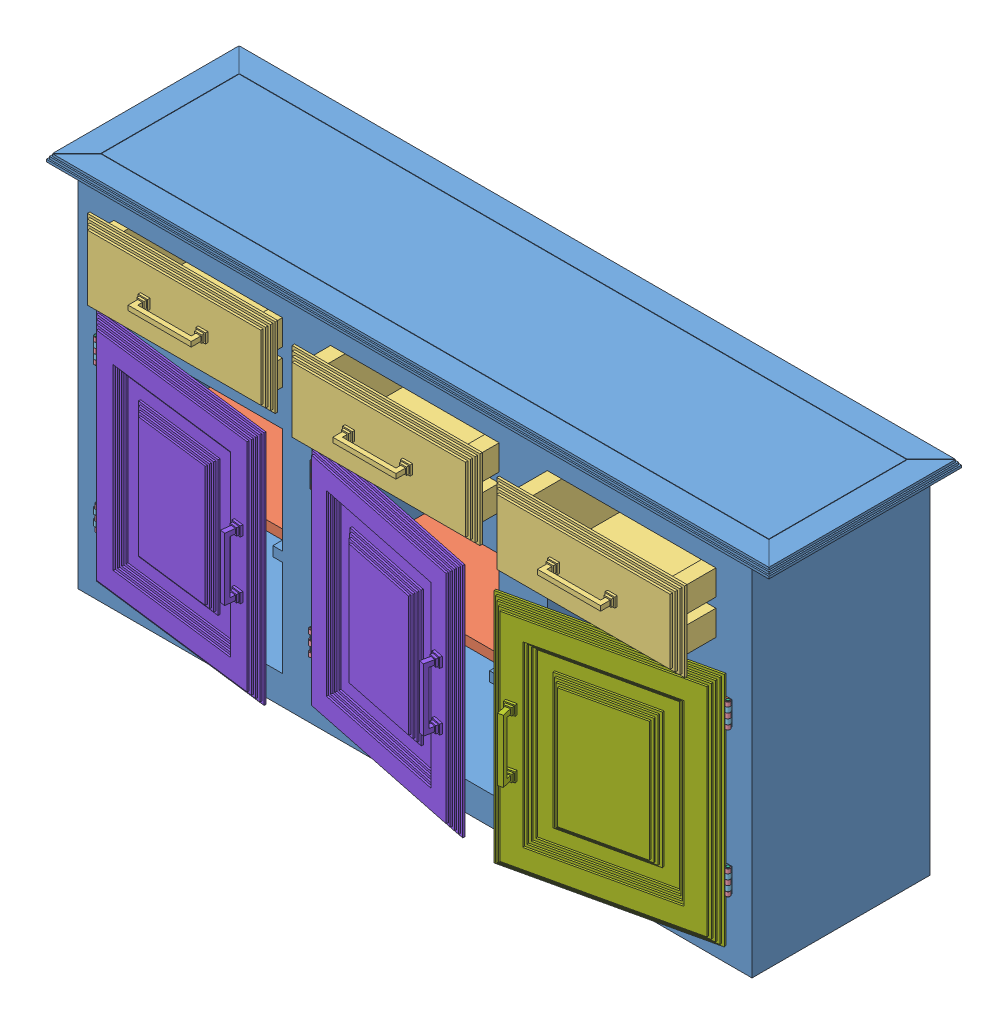
SolidWorks assembly Big.Cupboard, configuration Default. Lengths in mm.
Overall size (1500 765 525.59).
28 component instances, 8 part files, 91 mates.
Components (placement in the parent):
- Big.C-Part 01-1: Big.C-Part 01 [Default] at (578.0567 1072.5023 944.9709) size (1500 765 400)
- Big.C-Part 02-1: Big.C-Part 02 [Default] at (303.0567 602.5023 1109.9709) size (350 20 300)
- Big.C-Part 02-2: Big.C-Part 02 [Default] at (753.0567 602.5023 1109.9709) size (350 20 300)
- Big.C-Part 02-3: Big.C-Part 02 [Default] at (1203.0567 602.5023 1109.9709) size (350 20 300)
- Big.C-Part 03-1: Big.C-Part 03 [Default] at (128.0567 691.1413 859.9709) size (390 165 350)
- Big.C-Part 03-2: Big.C-Part 03 [Default] at (578.0567 691.1413 884.9709) size (390 165 350)
- Big.C-Part 03-3: Big.C-Part 03 [Default] at (1028.0567 691.1413 909.9709) size (390 165 350)
- HINGE HALF A-1: HINGE HALF A [Default] at (-77.5483 777.6273 1135.558) x (0.992303 0 0.123831) z (0 1 0) size (45.16 9.11 50.13)
- HINGE HALF B-1: HINGE HALF B [Default] at (-77.5483 777.5023 1135.558) x (0 0 -1) z (0 1 0) size (45.14 9.11 98.89)
- HINGE PIN-1: HINGE PIN [Default] at (-77.5483 804.6273 1135.558) x (0 -1 0) z (0.656059 0 0.75471) size (53.5 7 7)
- HINGE HALF A-2: HINGE HALF A [Default] at (372.4517 777.6273 1135.558) x (0.979214 0 0.202829) z (0 1 0) size (45.16 9.11 50.13)
- HINGE HALF B-2: HINGE HALF B [Default] at (372.4517 777.5023 1135.558) x (0 0 -1) z (0 1 0) size (45.14 9.11 98.89)
- HINGE PIN-2: HINGE PIN [Default] at (372.4517 804.6273 1135.558) x (0 -1 0) z (-0.009292 0 0.999957) size (53.5 7 7)
- HINGE HALF A-3: HINGE HALF A [Default] at (-74.6383 477.5023 1135.5734) x (0 0 -1) z (0 -1 0) size (45.16 9.11 50.13)
- HINGE HALF B-3: HINGE HALF B [Default] at (-77.533 477.6273 1135.5599) x (0.992303 0 0.123831) z (0 1 0) size (45.14 9.11 98.89)
- HINGE PIN-3: HINGE PIN [Default] at (-74.6383 504.5023 1135.5734) x (0 -1 0) z (0 0 1) size (53.5 7 7)
- HINGE HALF A-4: HINGE HALF A [Default] at (371.8614 477.6273 1138.4075) x (0.979214 0 0.202829) z (0 -1 0) size (45.16 9.11 50.13)
- HINGE HALF B-4: HINGE HALF B [Default] at (372.4517 477.5023 1135.558) x (0 0 -1) z (0 1 0) size (45.14 9.11 98.89)
- HINGE PIN-4: HINGE PIN [Default] at (372.4517 504.3773 1135.558) x (0 -1 0) z (0 0 1) size (53.5 7 7)
- HINGE HALF A-5: HINGE HALF A [Default] at (1233.6617 477.3773 1135.558) x (-0.975569 0 0.219695) z (0 1 0) size (45.16 9.11 50.13)
- HINGE PIN-5: HINGE PIN [Default] at (1233.6617 450.3773 1135.558) x (0 1 0) z (-0.755474 0 -0.655179) size (53.5 7 7)
- HINGE HALF A-6: HINGE HALF A [Default] at (1233.6617 777.3773 1135.558) x (-0.975569 0 0.219695) z (0 1 0) size (45.16 9.11 50.13)
- HINGE PIN-6: HINGE PIN [Default] at (1233.6617 750.3773 1135.558) x (0 1 0) z (-0.942472 0 0.334284) size (53.5 7 7)
- HINGE HALF B-7: HINGE HALF B [Default] at (1233.6617 777.5023 1135.558) x (0 0 -1) z (0 1 0) size (45.14 9.11 98.89)
- HINGE HALF B-8: HINGE HALF B [Default] at (1233.6617 477.5023 1135.558) x (0 0 -1) z (0 1 0) size (45.14 9.11 98.89)
- Big.C-Part 04_Right-4: Big.C-Part 04_Right [Default] at (1032.433 602.3773 1177.845) x (-0.975569 0 0.219695) z (0.219695 0 0.975569) size (400 490 50)
- Big.C-Part 04_Left-1: Big.C-Part 04_Left [Default] at (126.4774 610.7523 1160.9734) x (0.992303 0 0.123831) z (-0.123831 0 0.992303) size (400 490 50)
- Big.C-Part 04_Left-2: Big.C-Part 04_Left [Default] at (573.7898 610.7523 1177.2161) x (0.979214 0 0.202829) z (-0.202829 0 0.979214) size (400 490 50)
Mates (geometry in assembly coordinates):
- Coincident1: coincident anti-aligned: plane of Big.C-Part 01-1 through (-46.9433 602.5023 809.9709) normal (0 1 0); plane of Big.C-Part 02-1 through (303.0567 602.5023 1109.9709) normal (0 -1 0)
- Coincident2: coincident anti-aligned: plane of Big.C-Part 01-1 through (303.0567 822.5023 809.9709) normal (-1 0 0); plane of Big.C-Part 02-1 through (303.0567 622.5023 1109.9709) normal (1 0 0)
- Coincident3: coincident anti-aligned: plane of Big.C-Part 01-1 through (578.0567 1072.5023 809.9709) normal (0 0 1); plane of Big.C-Part 02-1 through (303.0567 622.5023 809.9709) normal (0 0 -1)
- Coincident4: coincident anti-aligned: plane of Big.C-Part 01-1 through (578.0567 1072.5023 809.9709) normal (0 0 1); plane of Big.C-Part 02-2 through (753.0567 622.5023 809.9709) normal (0 0 -1)
- Coincident5: coincident anti-aligned: plane of Big.C-Part 01-1 through (403.0567 822.5023 809.9709) normal (1 0 0); plane of Big.C-Part 02-2 through (403.0567 622.5023 1109.9709) normal (-1 0 0)
- Coincident6: coincident anti-aligned: plane of Big.C-Part 01-1 through (753.0567 602.5023 809.9709) normal (0 1 0); plane of Big.C-Part 02-2 through (753.0567 602.5023 1109.9709) normal (0 -1 0)
- Coincident7: coincident anti-aligned: plane of Big.C-Part 01-1 through (853.0567 602.5023 809.9709) normal (0 1 0); plane of Big.C-Part 02-3 through (1203.0567 602.5023 1109.9709) normal (0 -1 0)
- Coincident8: coincident anti-aligned: plane of Big.C-Part 01-1 through (578.0567 1072.5023 809.9709) normal (0 0 1); plane of Big.C-Part 02-3 through (1203.0567 622.5023 809.9709) normal (0 0 -1)
- Coincident9: coincident anti-aligned: plane of Big.C-Part 01-1 through (1203.0567 822.5023 809.9709) normal (-1 0 0); plane of Big.C-Part 02-3 through (1203.0567 622.5023 1109.9709) normal (1 0 0)
- Coincident10: coincident anti-aligned: plane of Big.C-Part 01-1 through (578.0567 1072.5023 809.9709) normal (0 0 1); plane of Big.C-Part 02-1 through (303.0567 622.5023 809.9709) normal (0 0 -1)
- Coincident11: coincident anti-aligned: plane of Big.C-Part 01-1 through (578.0567 1072.5023 809.9709) normal (0 0 1); plane of Big.C-Part 02-2 through (753.0567 622.5023 809.9709) normal (0 0 -1)
- Coincident12: coincident anti-aligned: plane of Big.C-Part 01-1 through (578.0567 1072.5023 809.9709) normal (0 0 1); plane of Big.C-Part 02-3 through (1203.0567 622.5023 809.9709) normal (0 0 -1)
- Coincident13: coincident anti-aligned: plane of Big.C-Part 01-1 through (303.0567 602.5023 809.9709) normal (0 1 0); plane of Big.C-Part 02-1 through (303.0567 602.5023 1109.9709) normal (0 -1 0)
- Coincident14: coincident anti-aligned: plane of Big.C-Part 01-1 through (753.0567 602.5023 809.9709) normal (0 1 0); plane of Big.C-Part 02-2 through (753.0567 602.5023 1109.9709) normal (0 -1 0)
- Coincident15: coincident anti-aligned: plane of Big.C-Part 01-1 through (1203.0567 602.5023 809.9709) normal (0 1 0); plane of Big.C-Part 02-3 through (1203.0567 602.5023 1109.9709) normal (0 -1 0)
- Coincident16: coincident anti-aligned: plane of Big.C-Part 01-1 through (-46.9433 970.0023 809.9709) normal (1 0 0); plane of Big.C-Part 03-1 through (-46.9433 970.0023 1179.9709) normal (-1 0 0)
- Coincident17: coincident anti-aligned: plane of Big.C-Part 01-1 through (-46.9433 1022.5023 809.9709) normal (0 -1 0); plane of Big.C-Part 03-1 through (-46.9433 1022.5023 1179.9709) normal (0 1 0)
- Distance1: distance = 50 mm anti-aligned: plane of Big.C-Part 01-1 through (578.0567 1072.5023 809.9709) normal (0 0 1); plane of Part3-1 through (128.0567 691.1413 859.9709) normal (0 0 -1)
- Distance2: distance = 75 mm anti-aligned: plane of Big.C-Part 01-1 through (578.0567 1072.5023 809.9709) normal (0 0 1); plane of Part3-2 through (578.0567 691.1413 884.9709) normal (0 0 -1)
- Coincident20: coincident anti-aligned: plane of Big.C-Part 01-1 through (403.0567 1022.5023 809.9709) normal (0 -1 0); plane of Big.C-Part 03-2 through (403.0567 1022.5023 1204.9709) normal (0 1 0)
- Coincident21: coincident anti-aligned: plane of Big.C-Part 01-1 through (403.0567 970.0023 809.9709) normal (1 0 0); plane of Big.C-Part 03-2 through (403.0567 970.0023 1204.9709) normal (-1 0 0)
- Distance3: distance = 100 mm anti-aligned: plane of Big.C-Part 01-1 through (578.0567 1072.5023 809.9709) normal (0 0 1); plane of Part3-3 through (1028.0567 691.1413 909.9709) normal (0 0 -1)
- Coincident23: coincident anti-aligned: plane of Big.C-Part 01-1 through (853.0567 970.0023 809.9709) normal (1 0 0); plane of Big.C-Part 03-3 through (853.0567 970.0023 1229.9709) normal (-1 0 0)
- Coincident24: coincident anti-aligned: plane of Big.C-Part 01-1 through (1203.0567 1022.5023 809.9709) normal (0 -1 0); plane of Big.C-Part 03-3 through (853.0567 1022.5023 1229.9709) normal (0 1 0)
- Coincident25: coincident anti-aligned: plane of Big.C-Part 01-1 through (-77.5933 718.7523 1109.9709) normal (1 0 0); plane of BUTT HINGE-3/HINGE HALF B-1 through (-49.9433 720.358 1109.7644) normal (-1 0 0)
- Coincident26: coincident anti-aligned: plane of Big.C-Part 01-1 through (-77.5933 802.5023 1094.9709) normal (0 0 1); plane of BUTT HINGE-3/HINGE HALF B-1 through (-49.9433 802.5023 1094.9709) normal (0 0 -1)
- Coincident27: coincident anti-aligned: plane of Big.C-Part 01-1 through (-77.5933 752.5023 1124.9709) normal (0 1 0); plane of BUTT HINGE-3/HINGE HALF B-1 through (-43.9433 752.5023 1128.8699) normal (0 -1 0)
- Coincident31: coincident anti-aligned: plane of Big.C-Part 01-1 through (-77.5933 718.7523 1109.9709) normal (1 0 0); plane of HINGE HALF B-1 through (-77.5933 802.5023 1128.8699) normal (-1 0 0)
- Coincident32: coincident anti-aligned: plane of Big.C-Part 01-1 through (-77.5933 802.5023 1094.9709) normal (0 -1 0); plane of HINGE HALF B-1 through (-71.5933 802.5023 1128.8699) normal (0 1 0)
- Coincident34: coincident anti-aligned: plane of Big.C-Part 01-1 through (-77.5933 802.5023 1094.9709) normal (0 0 1); plane of HINGE HALF B-1 through (-77.5933 802.5023 1094.9709) normal (0 0 -1)
- Coincident38: coincident anti-aligned: plane of HINGE HALF A-1 through (-82.7592 782.7523 1128.8612) normal (0 1 0); plane of HINGE HALF B-1 through (-83.5483 782.7523 1129.558) normal (0 -1 0)
- Concentric2: concentric anti-aligned: cylinder of HINGE HALF A-1 through (-77.5483 802.6273 1135.558) axis (0 -1 0) radius 2.955; cylinder of HINGE PIN-1 through (-77.5483 752.1273 1135.558) axis (0 1 0) radius 2.75
- Coincident39: coincident anti-aligned: plane of HINGE HALF A-1 through (-71.6492 802.6273 1142.2953) normal (0 1 0); plane of HINGE PIN-1 through (-77.5483 802.6273 1135.558) normal (0 -1 0)
- Concentric3: concentric anti-aligned: cylinder of HINGE HALF B-1 through (-77.5483 802.5023 1135.558) axis (0 -1 0) radius 2.955; cylinder of HINGE PIN-1 through (-77.5483 752.1273 1135.558) axis (0 1 0) radius 2.75
- Coincident40: coincident anti-aligned: plane of Big.C-Part 01-1 through (372.4067 718.7523 1109.9709) normal (1 0 0); plane of HINGE HALF B-2 through (372.4067 802.5023 1128.8699) normal (-1 0 0)
- Coincident41: coincident anti-aligned: plane of Big.C-Part 01-1 through (372.4067 802.5023 1094.9709) normal (0 -1 0); plane of HINGE HALF B-2 through (378.4067 802.5023 1128.8699) normal (0 1 0)
- Coincident42: coincident anti-aligned: plane of Big.C-Part 01-1 through (372.4067 802.5023 1094.9709) normal (0 0 1); plane of HINGE HALF B-2 through (372.4067 802.5023 1094.9709) normal (0 0 -1)
- Coincident46: coincident anti-aligned: plane of HINGE HALF A-2 through (367.7934 782.7523 1128.4657) normal (0 1 0); plane of HINGE HALF B-2 through (366.4517 782.7523 1129.558) normal (0 -1 0)
- Concentric4: concentric anti-aligned: cylinder of HINGE HALF A-2 through (372.4517 802.6273 1135.558) axis (0 -1 0) radius 2.955; cylinder of HINGE PIN-2 through (372.4517 752.1273 1135.558) axis (0 1 0) radius 2.75
- Coincident47: coincident anti-aligned: plane of HINGE HALF A-2 through (377.7929 802.6273 1142.7457) normal (0 1 0); plane of HINGE PIN-2 through (372.4517 802.6273 1135.558) normal (0 -1 0)
- Concentric5: concentric anti-aligned: cylinder of HINGE HALF B-2 through (372.4517 802.5023 1135.558) axis (0 -1 0) radius 2.955; cylinder of HINGE PIN-2 through (372.4517 752.1273 1135.558) axis (0 1 0) radius 2.75
- Coincident48: coincident anti-aligned: plane of Big.C-Part 01-1 through (-77.5933 418.7523 1109.9709) normal (1 0 0); plane of HINGE HALF A-3 through (-77.5933 452.5023 1129.9863) normal (-1 0 0)
- Coincident49: coincident anti-aligned: plane of Big.C-Part 01-1 through (-77.5933 502.5023 1094.9709) normal (0 -1 0); plane of HINGE HALF A-3 through (-80.5933 502.5023 1128.8854) normal (0 1 0)
- Coincident50: coincident anti-aligned: plane of Big.C-Part 01-1 through (-77.5933 502.5023 1094.9709) normal (0 0 1); plane of HINGE HALF A-3 through (-74.5933 502.5023 1094.9709) normal (0 0 -1)
- Coincident54: coincident anti-aligned: plane of HINGE HALF A-3 through (-80.5933 502.5023 1128.8854) normal (0 1 0); plane of HINGE PIN-3 through (-74.6383 502.5023 1135.5734) normal (0 -1 0)
- Concentric14: concentric aligned: cylinder of HINGE HALF A-3 through (-74.6383 452.5023 1135.5734) axis (0 1 0) radius 2.955; cylinder of HINGE PIN-3 through (-74.6383 452.0023 1135.5734) axis (0 1 0) radius 2.75
- Coincident59: coincident anti-aligned: plane of HINGE HALF A-3 through (-80.5933 502.5023 1128.8854) normal (0 1 0); plane of HINGE PIN-3 through (-74.6383 502.5023 1135.5734) normal (0 -1 0)
- Coincident61: coincident anti-aligned: plane of Big.C-Part 01-1 through (372.4067 418.7523 1109.9709) normal (1 0 0); plane of HINGE HALF B-4 through (372.4067 502.5023 1128.8699) normal (-1 0 0)
- Coincident62: coincident anti-aligned: plane of Big.C-Part 01-1 through (372.4067 502.5023 1094.9709) normal (0 -1 0); plane of HINGE HALF B-4 through (378.4067 502.5023 1128.8699) normal (0 1 0)
- Coincident63: coincident anti-aligned: plane of Big.C-Part 01-1 through (372.4067 502.5023 1094.9709) normal (0 0 1); plane of HINGE HALF B-4 through (372.4067 502.5023 1094.9709) normal (0 0 -1)
- Coincident71: coincident anti-aligned: plane of Big.C-Part 04_Right-3 through (1227.1173 536.1273 1144.4319) normal (-0.348248 0 0.937402); plane of HINGE HALF A-5 through (1227.1469 502.3773 1137.0712) normal (0.219695 0 0.975569)
- Coincident72: coincident anti-aligned: plane of Big.C-Part 04_Right-3 through (1208.3692 452.3773 1137.4669) normal (0 1 0); plane of HINGE HALF A-5 through (1225.8287 452.3773 1131.2178) normal (0 -1 0)
- Coincident73: coincident anti-aligned: plane of Big.C-Part 04_Right-3 through (1241.1783 452.3773 1149.6556) normal (-0.937402 0 -0.348248); plane of HINGE HALF A-5 through (1194.061 452.3773 1144.5221) normal (-0.975569 0 0.219695)
- Concentric16: concentric aligned: cylinder of HINGE HALF A-5 through (1233.6617 502.3773 1135.558) axis (0 -1 0) radius 2.955; cylinder of HINGE PIN-5 through (1233.6617 502.8773 1135.558) axis (0 -1 0) radius 2.75
- Coincident74: coincident anti-aligned: plane of HINGE HALF A-5 through (1225.8287 452.3773 1131.2178) normal (0 -1 0); plane of HINGE PIN-5 through (1233.6617 452.3773 1135.558) normal (0 1 0)
- Coincident75: coincident anti-aligned: plane of HINGE HALF A-5 through (1240.8333 461.2523 1140.0932) normal (0 1 0); plane of HINGE HALF B-5 through (1202.8204 86.954 1238.0913) normal (-0.008727 -0.999962 0)
- Concentric17: concentric anti-aligned: cylinder of HINGE HALF B-5 through (1196.7421 78.0067 1232.0913) axis (0.008727 0.999962 0) radius 2.955; cylinder of HINGE PIN-5 through (1233.6617 502.8773 1135.558) axis (0 -1 0) radius 2.75
- Coincident79: coincident anti-aligned: plane of Big.C-Part 04_Right-3 through (1395.8497 602.3773 1207.1165) normal (-0.348248 0 0.937402); plane of HINGE HALF A-6 through (1227.1469 802.3773 1137.0712) normal (0.219695 0 0.975569)
- Coincident80: coincident anti-aligned: plane of Big.C-Part 04_Right-3 through (1208.3692 752.3773 1137.4669) normal (0 1 0); plane of HINGE HALF A-6 through (1225.8287 752.3773 1131.2178) normal (0 -1 0)
- Coincident81: coincident anti-aligned: plane of Big.C-Part 04_Right-3 through (1241.1783 752.3773 1149.6556) normal (-0.937402 0 -0.348248); plane of HINGE HALF A-6 through (1194.061 752.3773 1144.5221) normal (-0.975569 0 0.219695)
- Concentric18: concentric aligned: cylinder of HINGE HALF A-6 through (1233.6617 802.3773 1135.558) axis (0 -1 0) radius 2.955; cylinder of HINGE PIN-6 through (1233.6617 802.8773 1135.558) axis (0 -1 0) radius 2.75
- Coincident82: coincident anti-aligned: plane of HINGE HALF A-6 through (1225.8287 752.3773 1131.2178) normal (0 -1 0); plane of HINGE PIN-6 through (1233.6617 752.3773 1135.558) normal (0 1 0)
- Concentric19: concentric anti-aligned: cylinder of HINGE HALF B-6 through (1202.71 428.5754 1227.0048) axis (0.008727 0.999962 0) radius 2.955; cylinder of HINGE PIN-6 through (1233.6617 802.8773 1135.558) axis (0 -1 0) radius 2.75
- Concentric20: concentric anti-aligned: cylinder of HINGE HALF B-6 through (1202.71 428.5754 1227.0048) axis (0.008727 0.999962 0) radius 2.955; cylinder of HINGE PIN-6 through (1233.6617 802.8773 1135.558) axis (0 -1 0) radius 2.75
- Concentric21: concentric aligned: cylinder of HINGE PIN-6 through (1233.6617 802.8773 1135.558) axis (0 -1 0) radius 2.75; cylinder of HINGE HALF B-7 through (1233.6617 802.5023 1135.558) axis (0 -1 0) radius 2.955
- Coincident85: coincident anti-aligned: plane of HINGE HALF A-6 through (1240.8333 793.5023 1140.0932) normal (0 -1 0); plane of HINGE HALF B-7 through (1227.6617 793.5023 1141.558) normal (0 1 0)
- Concentric22: concentric aligned: cylinder of HINGE PIN-5 through (1233.6617 502.8773 1135.558) axis (0 -1 0) radius 2.75; cylinder of HINGE HALF B-8 through (1233.6617 502.5023 1135.558) axis (0 -1 0) radius 2.955
- Coincident86: coincident anti-aligned: plane of HINGE HALF A-5 through (1240.8333 493.5023 1140.0932) normal (0 -1 0); plane of HINGE HALF B-8 through (1227.6617 493.5023 1141.558) normal (0 1 0)
- Coincident90: coincident anti-aligned: plane of Big.C-Part 01-1 through (1236.6167 718.7523 1109.9709) normal (-1 0 0); plane of HINGE HALF B-7 through (1236.6167 802.5023 1129.9709) normal (1 0 0)
- Coincident91: coincident anti-aligned: plane of Big.C-Part 01-1 through (1236.6167 802.5023 1129.9709) normal (0 -1 0); plane of HINGE HALF B-7 through (1239.6167 802.5023 1128.8699) normal (0 1 0)
- Coincident92: coincident anti-aligned: plane of Big.C-Part 01-1 through (1236.6167 802.5023 1094.9709) normal (0 0 1); plane of HINGE HALF B-7 through (1233.6167 802.5023 1094.9709) normal (0 0 -1)
- Coincident93: coincident anti-aligned: plane of Big.C-Part 01-1 through (1236.6167 418.7523 1109.9709) normal (-1 0 0); plane of HINGE HALF B-8 through (1236.6167 502.5023 1129.9709) normal (1 0 0)
- Coincident94: coincident: line of Big.C-Part 01-1 through (1203.0567 502.5023 1129.9709) axis (0 0 -1); plane of HINGE HALF B-8 through (1239.6167 502.5023 1128.8699) normal (0 1 0)
- Concentric24: concentric anti-aligned: cylinder of HINGE HALF B-4 through (372.4517 502.5023 1135.558) axis (0 -1 0) radius 2.955; cylinder of HINGE PIN-4 through (372.4517 451.8773 1135.558) axis (0 1 0) radius 2.75
- Coincident98: coincident anti-aligned: plane of Big.C-Part 01-1 through (1236.6167 502.5023 1094.9709) normal (0 0 1); plane of HINGE HALF B-8 through (1233.6167 502.5023 1094.9709) normal (0 0 -1)
- Coincident99: coincident anti-aligned: plane of HINGE HALF A-6 through (1227.1469 802.3773 1137.0712) normal (0.219695 0 0.975569); plane of Big.C-Part 04_Right-4 through (1033.0921 602.3773 1180.7717) normal (-0.219695 0 -0.975569)
- Coincident101: coincident anti-aligned: plane of HINGE HALF A-6 through (1225.8287 802.3773 1131.2178) normal (0 1 0); plane of Big.C-Part 04_Right-4 through (1228.2059 802.3773 1136.8327) normal (0 -1 0)
- Coincident102: coincident anti-aligned: plane of HINGE HALF A-6 through (1194.061 752.3773 1144.5221) normal (-0.975569 0 0.219695); plane of Big.C-Part 04_Right-4 through (1194.061 752.3773 1144.5221) normal (0.975569 0 -0.219695)
- Coincident103: coincident anti-aligned: plane of HINGE HALF A-5 through (1227.1469 502.3773 1137.0712) normal (0.219695 0 0.975569); plane of Big.C-Part 04_Right-4 through (1033.0921 602.3773 1180.7717) normal (-0.219695 0 -0.975569)
- Coincident106: coincident anti-aligned: plane of HINGE HALF A-1 through (-72.3701 802.6273 1139.1821) normal (-0.123831 0 0.992303); plane of Big.C-Part 04_Left-1 through (-52.5087 718.8773 1141.6606) normal (0.123831 0 -0.992303)
- Coincident107: coincident anti-aligned: plane of HINGE HALF A-1 through (-71.6492 802.6273 1142.2953) normal (0 1 0); plane of Big.C-Part 04_Left-1 through (-72.3548 802.6273 1139.184) normal (0 -1 0)
- Coincident108: coincident anti-aligned: plane of HINGE HALF A-1 through (-37.2527 752.6273 1140.5412) normal (0.992303 0 0.123831); plane of Big.C-Part 04_Left-1 through (-37.6242 802.6273 1143.5181) normal (-0.992303 0 -0.123831)
- Coincident113: coincident anti-aligned: plane of HINGE HALF B-3 through (-72.3548 502.6273 1139.184) normal (-0.123831 0 0.992303); plane of Big.C-Part 04_Left-1 through (-52.5087 418.8773 1141.6606) normal (0.123831 0 -0.992303)
- Coincident114: coincident anti-aligned: plane of HINGE HALF B-3 through (-71.6338 502.6273 1142.2972) normal (0 1 0); plane of Big.C-Part 04_Left-1 through (-72.3548 502.6273 1139.184) normal (0 -1 0)
- Coincident115: coincident anti-aligned: plane of HINGE HALF B-3 through (-37.2527 502.6273 1140.5412) normal (0.992303 0 0.123831); plane of Big.C-Part 04_Left-1 through (-37.6242 502.6273 1143.5181) normal (-0.992303 0 -0.123831)
- Coincident116: coincident anti-aligned: plane of HINGE HALF A-2 through (377.3233 802.6273 1139.5848) normal (-0.202829 0 0.979214); plane of Big.C-Part 04_Left-2 through (396.9227 718.8773 1143.6445) normal (0.202829 0 -0.979214)
- Coincident117: coincident anti-aligned: plane of HINGE HALF A-2 through (377.7929 802.6273 1142.7457) normal (0 1 0); plane of Big.C-Part 04_Left-2 through (377.3384 802.6273 1139.5879) normal (0 -1 0)
- Coincident118: coincident anti-aligned: plane of HINGE HALF A-2 through (412.2194 752.6273 1143.7493) normal (0.979214 0 0.202829); plane of Big.C-Part 04_Left-2 through (411.6109 802.6273 1146.6869) normal (-0.979214 0 -0.202829)
- Coincident119: coincident anti-aligned: plane of HINGE HALF A-4 through (378.4013 452.6273 1139.8081) normal (-0.202829 0 0.979214); plane of Big.C-Part 04_Left-2 through (396.9227 418.8773 1143.6445) normal (0.202829 0 -0.979214)
- Coincident120: coincident anti-aligned: plane of HINGE HALF A-4 through (411.6109 502.6273 1146.6869) normal (0.979214 0 0.202829); plane of Big.C-Part 04_Left-2 through (411.6109 502.6273 1146.6869) normal (-0.979214 0 -0.202829)
- Coincident121: coincident anti-aligned: plane of HINGE HALF A-4 through (379.6183 502.6273 1133.9328) normal (0 1 0); plane of Big.C-Part 04_Left-2 through (377.3384 502.6273 1139.5879) normal (0 -1 0)
